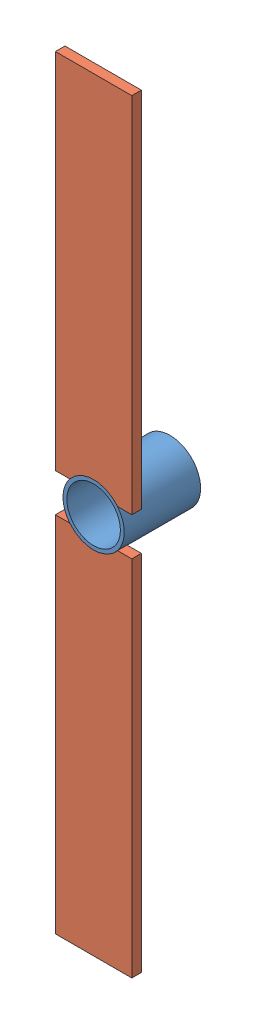
SolidWorks assembly Сборка - фланец, configuration По умолчанию. Lengths in mm.
Overall size (40 400 40).
3 component instances, 2 part files, 5 mates.
Components (placement in the parent):
- Фланец-1: Фланец [По умолчанию] at (-4.4391 -1.3212 -2.24) size (32 32 40)
- Деталь фланца-2: Деталь фланца [По умолчанию] at (15.5609 -201.3212 37.76) x (-1 0 0) z (0 1 0) size (40 5 190)
- Деталь фланца-3: Деталь фланца [По умолчанию] at (-24.4391 198.6788 37.76) x (1 0 0) z (0 -1 0) size (40 5 190)
Mates (geometry in assembly coordinates):
- Совпадение2: coincident aligned: plane of Фланец-1 through (-4.4391 -1.3212 37.76) normal (0 0 1); plane of Деталь фланца-3 through (-24.4391 -1.3212 37.76) normal (0 0 1)
- Совпадение3: coincident aligned: plane of Фланец-1 through (-4.4391 -1.3212 37.76) normal (0 0 1); plane of Деталь фланца-2 through (5.5609 15.9993 37.76) normal (0 0 1)
- Совпадение6: coincident aligned: circle of Фланец-1; circle of Деталь фланца-2
- Совпадение9: coincident aligned: circle of Фланец-1; circle of Деталь фланца-3
- Совпадение10: coincident anti-aligned: line of Деталь фланца-2 through (15.5609 -11.3212 37.76) axis (0 -1 0); line of Деталь фланца-3 through (15.5609 8.6788 37.76) axis (0 1 0)
